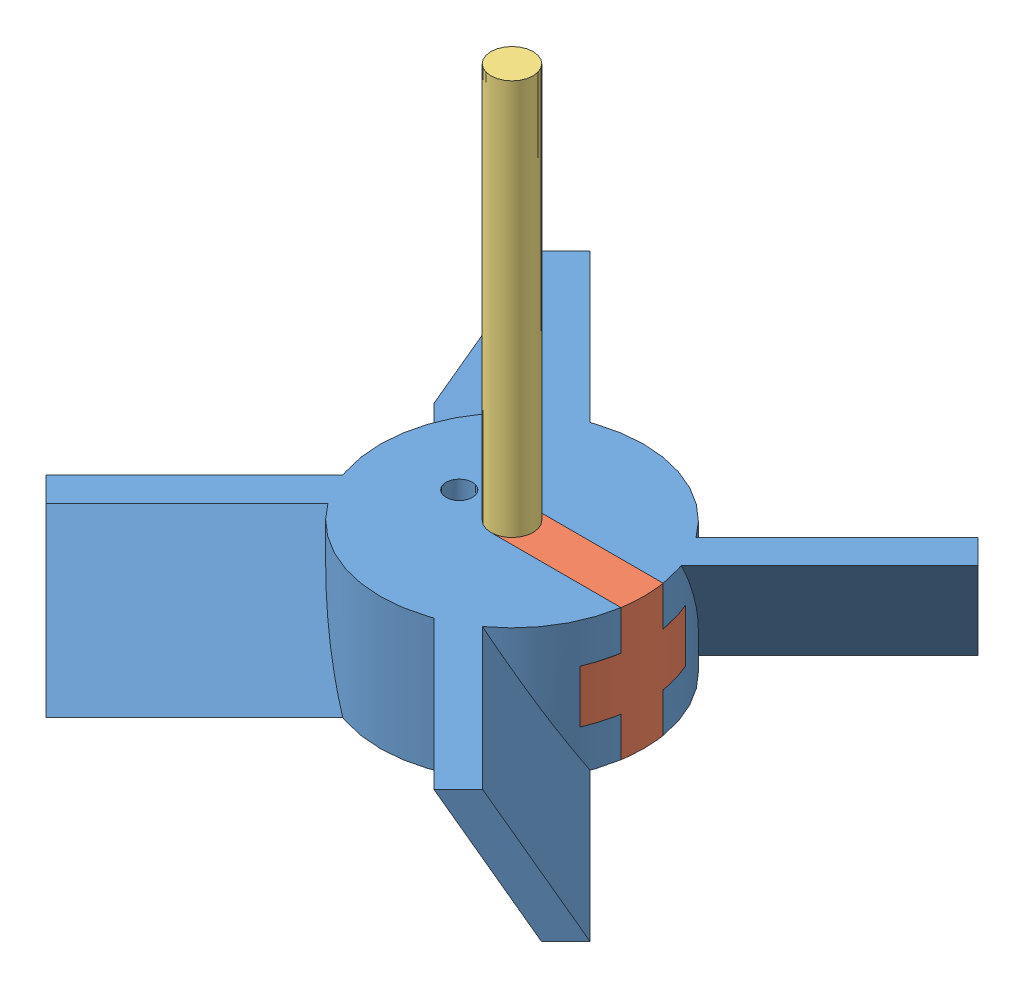
SolidWorks assembly Combined, configuration Default. Lengths in mm.
Overall size (41.28 40 41.28).
3 component instances, 3 part files, 5 mates.
Components (placement in the parent):
- Impeller-1: Impeller [Default] at (19.9801 16.5701 32.6547) size (41.28 10 41.28)
- Inner-1: Inner [Default] at (19.9801 16.5701 32.6547) x (-1 0 0) z (0 0 -1) size (17 10 8)
- Shaft-1: Shaft [Default] at (19.9801 16.5701 32.6547) size (3.2 40 3.2)
Mates (geometry in assembly coordinates):
- Coincident1: coincident anti-aligned: circle of Impeller-1; circle of Inner-1
- Coincident2: coincident anti-aligned: line of Impeller-1 through (29.1453 23.5701 28.6547) axis (0 -1 0); line of Inner-1 through (29.1453 19.5701 28.6547) axis (0 1 0)
- Coincident3: coincident aligned: circle of Impeller-1; circle of Shaft-1
- Concentric1: concentric aligned: cylinder of Impeller-1 through (19.9801 26.5701 32.6547) axis (0 -1 0) radius 10; cylinder of Shaft-1 through (19.9801 56.5701 32.6547) axis (0 -1 0) radius 1.6
- Coincident4: coincident anti-aligned: circle of Inner-1; cylinder of Shaft-1 through (19.9801 56.5701 32.6547) axis (0 -1 0) radius 1.6
